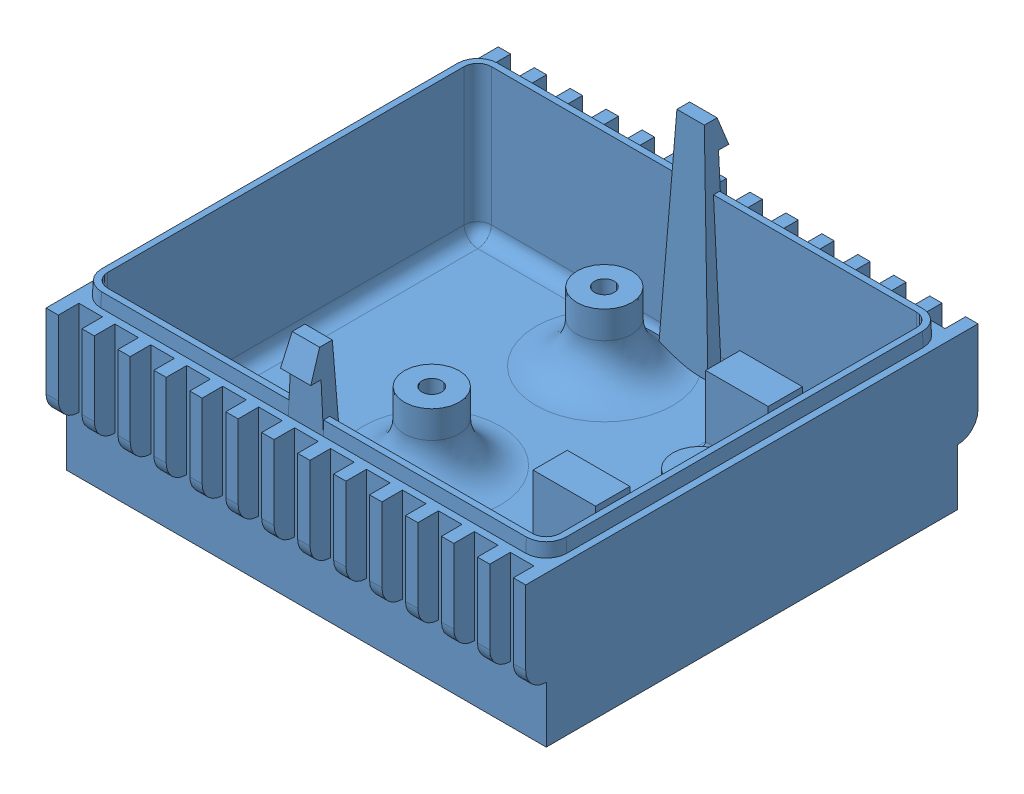
SolidWorks assembly c64psu, configuration Default. Lengths in mm.
Overall size (70 44.41 66).
4 component instances, 3 part files, 0 mates.
Components (placement in the parent):
- regulator board-1: regulator board [Default] at (19.2565 12.138 27.197) size (43 1.6 21) (hidden)
- regulator board-4: regulator board [Default] at (19.3254 12.3163 52.3828) size (43 1.6 21) (hidden)
- small_body-1: small_body [Default] at (8.9487 0.0673 28.6896) x (0 0 1) z (-1 0 0) size (66 44.41 70)
- channel lock AIO-CSM12-1: channel lock AIO-CSM12 [Default] at (-26.1102 12.4406 28.8156) x (0 -1 0) z (0 0 1) size (15 28 15) (hidden)
